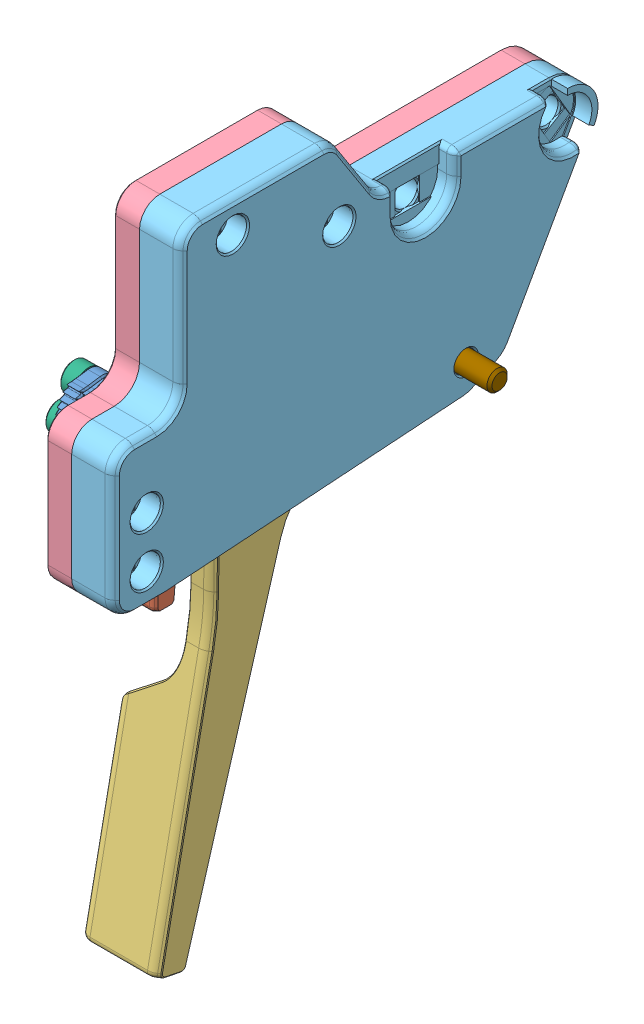
SolidWorks assembly Tightener, configuration Default. Lengths in mm.
Overall size (36 130.2 95.4).
15 component instances, 11 part files, 0 mates.
Components (placement in the parent):
- Tightener Toothed Plate^Zip Tie Installer-1: Tightener Toothed Plate^Zip Tie Installer [Default] at (-3 0 0) size (3 10.84 9.72)
- Tightener Toothed Plate^Zip Tie Installer-2: Tightener Toothed Plate^Zip Tie Installer [Default] at origin size (3 10.84 9.72)
- Tightener Outer Arm^Zip Tie Installer-1: Tightener Outer Arm^Zip Tie Installer [Default] at origin size (12 57.11 23.24)
- Tightener Lever^Zip Tie Installer-1: Tightener Lever^Zip Tie Installer [Default] at origin size (15.83 108.95 63.63)
- Tightener Hinge Plate^Zip Tie Installer-1: Tightener Hinge Plate^Zip Tie Installer [Default] at origin size (5 60.99 95.4)
- Tightener Cover^Zip Tie Installer-1: Tightener Cover^Zip Tie Installer [Default] at origin size (8.4 60.99 95.4)
- socket head cap screw_am(B18.3.1M - 3 x 0.5 x 16 Hex SHCS -- 16NHX)-1: socket head cap screw_am(B18.3.1M - 3 x 0.5 x 16 Hex SHCS -- 16NHX) [Default] at (-6 -48.8276 -37) size (19 5.5 5.5)
- socket head cap screw_am(B18.3.1M - 3 x 0.5 x 16 Hex SHCS -- 16NHX)-2: socket head cap screw_am(B18.3.1M - 3 x 0.5 x 16 Hex SHCS -- 16NHX) [Default] at (-6 -43.5888 -39.925) size (19 5.5 5.5)
- socket head cap screw_am(B18.3.1M - 3 x 0.5 x 5 Hex SHCS -- 5NHX)-1: socket head cap screw_am(B18.3.1M - 3 x 0.5 x 5 Hex SHCS -- 5NHX) [Default] at (18.8 -30.7609 -85.0495) x (-1 0 0) z (0 0 -1) size (8 5.5 5.5)
- socket head cap screw_am(B18.3.1M - 3 x 0.5 x 5 Hex SHCS -- 5NHX)-2: socket head cap screw_am(B18.3.1M - 3 x 0.5 x 5 Hex SHCS -- 5NHX) [Default] at (18.8 -18.048 -52.44) x (-1 0 0) z (0 0 -1) size (8 5.5 5.5)
- 94180A331_HEAT-SET INSERTS FOR PLASTICS-1: 94180A331_HEAT-SET INSERTS FOR PLASTICS [Default] at (15 -48.8276 -37) x (0 1 0) z (0 0 -1) size (5.56 4.12 5.56)
- 94180A331_HEAT-SET INSERTS FOR PLASTICS-2: 94180A331_HEAT-SET INSERTS FOR PLASTICS [Default] at (15 -43.5888 -39.925) x (0 1 0) z (0 0 -1) size (5.56 4.12 5.56)
- Dowel Pin 4mm(20mm)-1: Dowel Pin 4mm(20mm) [Default] at (20 -50.7609 -88) x (0 0 1) z (-1 0 0) size (4 4 20)
- Dowel Pin 3mm(9mm)-1: Dowel Pin 3mm(9mm) [Default] at (15.5 -24.9328 -45.1875) x (0 0 1) z (-1 0 0) size (3 3 9)
- Extension Spring(35mm)-1: Extension Spring(35mm) [Default] at (15.4 -19.5009 -56.1668) x (0 -0.931701 0.363226) z (1 0 0) size (6.36 39.59 6.36)
